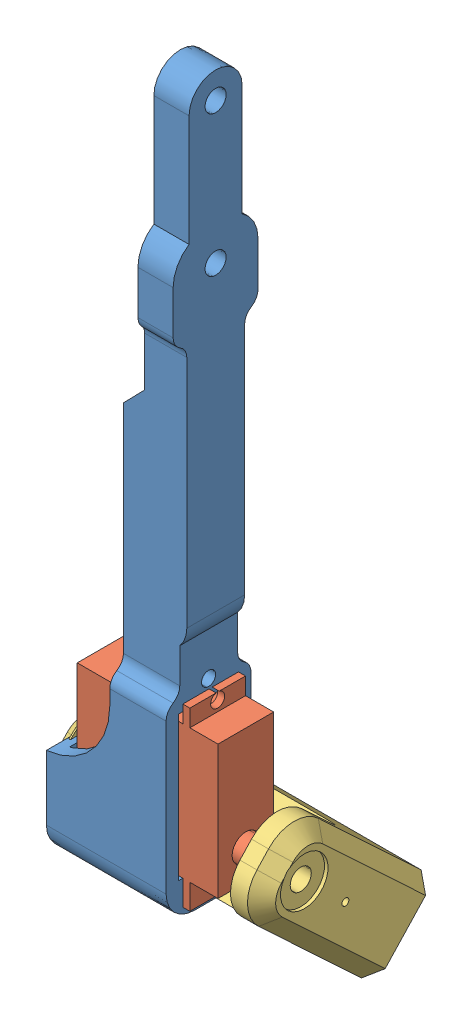
SolidWorks assembly Assem1, configuration 默认. Lengths in mm.
Overall size (32.03 111.79 26.74).
3 component instances, 3 part files, 4 mates.
Components (placement in the parent):
- 机械臂2自由 4g-1: 机械臂2自由 4g [默认] at (5.3155 -36.8141 102.9057) size (18 102.91 12.07)
- 4 g舵机-1: 4 g舵机 [默认] at (0.3555 -9.716 95.6723) x (0 0 1) z (1 0 0) size (7.91 25 23)
- 俯仰4g-1: 俯仰4g [默认] at (2.8595 -28.5469 93.4127) x (0 -0.682879 -0.730531) z (0 -0.730531 0.682879) size (25 32.03 12.41)
Mates (geometry in assembly coordinates):
- Coincident1: coincident anti-aligned: plane of 机械臂2自由 4g-1 through (13.3155 -36.8141 102.9057) normal (1 0 0); plane of 4 g舵机-1 through (13.3155 -28.9105 70.6523) normal (-1 0 0)
- Coincident2: coincident anti-aligned: plane of 机械臂2自由 4g-1 through (5.3155 -4.8402 95.6723) normal (0 0 1); plane of 4 g舵机-1 through (0.3555 -9.716 95.6723) normal (0 0 -1)
- Coincident4: coincident anti-aligned: plane of 机械臂2自由 4g-1 through (5.3155 -25.3402 95.6723) normal (0 1 0); plane of 4 g舵机-1 through (18.3155 -25.3402 103.5823) normal (0 -1 0)
- Concentric2: concentric aligned: cylinder of 4 g舵机-1 through (21.3155 -21.0492 99.6273) axis (-1 0 0) radius 1.9516; cylinder of 俯仰4g-1 through (26.6185 -21.0492 99.6273) axis (-1 0 0) radius 1.5
